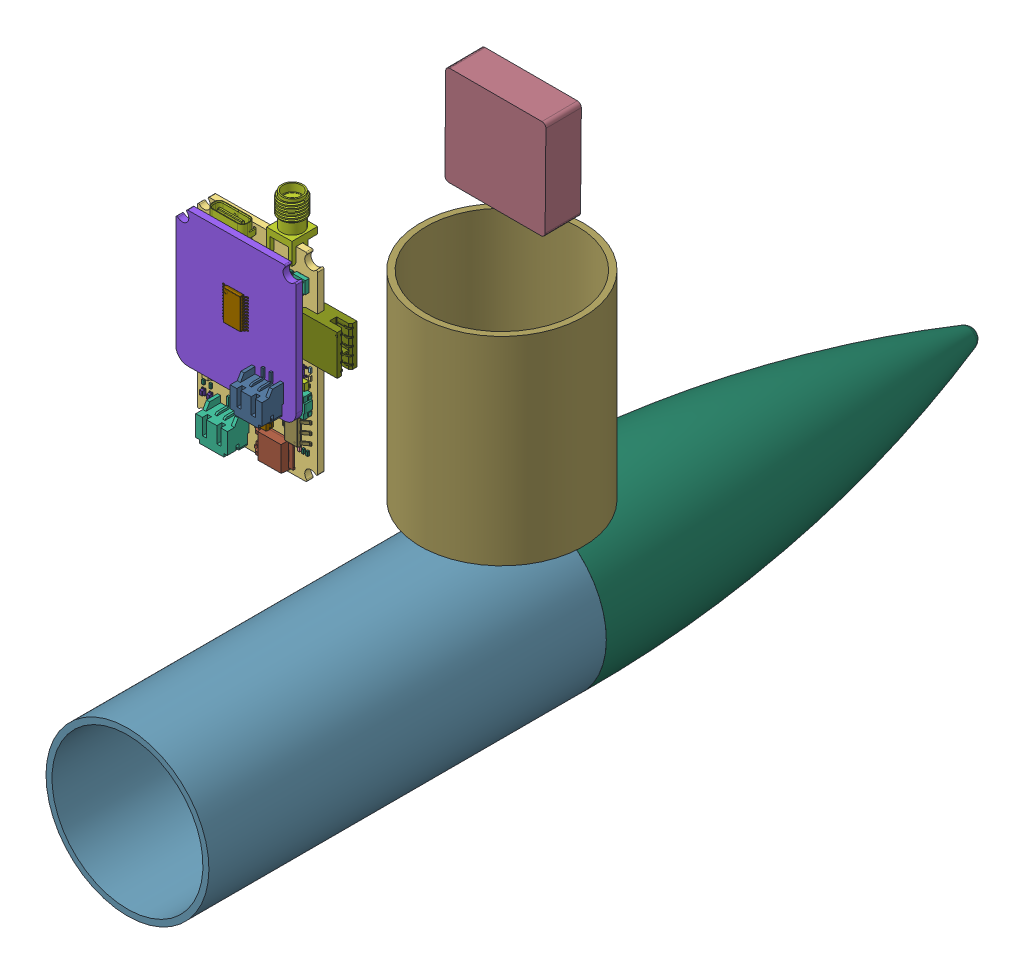
SolidWorks assembly 0. Nosecone & Avionics Bay Assembly, configuration Default. Lengths in mm.
Overall size (73.27 162.42 213).
85 component instances, 51 part files, 7 mates.
Components (placement in the parent):
- Barrel-jack female-1: Barrel-jack female [Default] at (-3.0127 -6.7721 47.1795) size (11 11 23.95)
- 18650 Long-1: 18650 Long [Default] at (0 0 34.458) x (0.762062 0.647505 0) z (-0.647505 0.762062 0) size (18.9 70 18.9)
- Firefly-mini-MBA-1: Firefly-mini-MBA [Default] at (-13.2772 55.7989 31.9723) x (0.999962 0 -0.008727) z (0.008727 0 0.999962) size (54.52 77.58 19.6)
  - Firefly-mini-1: Firefly-mini [Default] at (-8.0346 2.0358 39.383) size (54.52 77.58 14.1)
    - Firefly-mini_BOARD-1: Firefly-mini_BOARD [Default] at origin size (30 50 1.6)
    - QFP50P1200X1200X160-64N_CMP-020-00025-2-1: QFP50P1200X1200X160-64N_CMP-020-00025-2 [Default] at (24.892 39.878 1.5689) x (0 -1 0) z (0 0 1) size (11.99 11.99 1.61)
    - BMP388_CMP-004-000000-2-1: BMP388_CMP-004-000000-2 [Default] at (15.748 49.784 1.5689) size (2 2 1.1)
    - JST-_S2B-PH-SM4-TB(LF)(SN)-2_V_CMP-1755-00001-1-1: JST-_S2B-PH-SM4-TB(LF)(SN)-2_V_CMP-1755-00001-1 [Default] at (19 14.5 1.5689) size (7.9 8.6 5.6)
    - VALCON_CSP-USC16-TR_CMP-042-000000-3-1: VALCON_CSP-USC16-TR_CMP-042-000000-3 [Default] at (19.967 53.594 1.5689) x (-1 0 0) z (0 0 1) size (8.94 7.75 4.26)
    - RES-0402_CMP-009-00235-1-1: RES-0402_CMP-009-00235-1 [Default] at (17.145 52.578 1.5689) size (1.1 0.55 0.4)
    - RES-0402_CMP-009-00235-1-2: RES-0402_CMP-009-00235-1 [Default] at (22.225 52.578 1.5689) x (-1 0 0) z (0 0 1) size (1.1 0.55 0.4)
    - FP-TAJA-MFG_CMP-001-00183-1-1: FP-TAJA-MFG_CMP-001-00183-1 [Default] at (27.432 18.542 1.5689) x (-1 0 0) z (0 0 1) size (3.2 1.6 1.8)
    - KEMT-T491-B_M_CMP-001-00181-1-1: KEMT-T491-B_M_CMP-001-00181-1 [Default] at (27.813 21.336 1.5689) x (-1 0 0) z (0 0 1) size (4.14 3 2.1)
    - FP-L78M05ABDT-TR-MFG_CMP-019-00057-2-1: FP-L78M05ABDT-TR-MFG_CMP-019-00057-2 [Default] at (30.2115 14.083 1.5689) x (0 -1 0) z (0 0 1) size (6.54 9.67 2.3)
    - FP-AMS1117-IPC_B_CMP-019-00058-1-1: FP-AMS1117-IPC_B_CMP-019-00058-1 [Default] at (35.052 21.209 1.5689) x (-1 0 0) z (0 0 1) size (7.05 6.59 2.14)
    - LoRa-CC68-868-TCXO-Footprint-1_CMP-00025-00003-3-2: LoRa-CC68-868-TCXO-Footprint-1_CMP-00025-00003-3 [Default] at (21.717 43.815 0.0305) x (1 0 0) z (0 0 -1) size (16 16 2.1)
    - QUEC-L80-M39-12_V_CMP-021-00008-3-1: QUEC-L80-M39-12_V_CMP-021-00008-3 [Default] at (25 22.5 0.0305) x (-1 0 0) z (0 0 -1) size (16 16 6.95)
    - CAP-0402_CMP-001-00142-1-1: CAP-0402_CMP-001-00142-1 [Default] at (17.399 49.911 1.5689) x (0 1 0) z (0 0 1) size (1.05 0.55 0.55)
    - CAP-0402_CMP-001-00142-1-2: CAP-0402_CMP-001-00142-1 [Default] at (15.24 51.562 1.5689) size (1.05 0.55 0.55)
    - 009159010061911-Footprint-1_CMP-002-00088-4-1: 009159010061911-Footprint-1_CMP-002-00088-4 [Default] at (37.715 43 1.5689) x (0 -1 0) z (0 0 1) size (10 10 5)
    - FP-SOT23-IPC_C_CMP-013-00038-1-1: FP-SOT23-IPC_C_CMP-013-00038-1 [Default] at (36.068 34.036 1.5689) x (-1 0 0) z (0 0 1) size (2.82 2.9 1.25)
    - FP-YZT0012A-IPC_C_CMP-016-00011-1-1: FP-YZT0012A-IPC_C_CMP-016-00011-1 [Default] at (34.3123 48.6187 1.5689) x (0.707107 0.707107 0) z (0 0 1) size (1.38 1.88 0.64)
    - RES-0402_CMP-009-00211-1-1: RES-0402_CMP-009-00211-1 [Default] at (15.367 48.133 1.5689) size (1.1 0.55 0.4)
    - RES-0402_CMP-009-00211-1-2: RES-0402_CMP-009-00211-1 [Default] at (17.018 51.562 1.5689) size (1.1 0.55 0.4)
    - SOT95P280X145-5N_CMP-122-000000-3-1: SOT95P280X145-5N_CMP-122-000000-3 [Default] at (30.495 26.101 1.5689) x (-1 0 0) z (0 0 1) size (2.8 2.9 1.2)
    - RES-0402_CMP-009-00191-1-1: RES-0402_CMP-009-00191-1 [Default] at (32.766 52.451 1.5689) x (0 1 0) z (0 0 1) size (1.1 0.55 0.4)
    - RES-0402_CMP-009-00191-1-2: RES-0402_CMP-009-00191-1 [Default] at (38.354 33.274 1.5689) x (0 1 0) z (0 0 1) size (1.1 0.55 0.4)
    - RES-0402_CMP-009-00191-1-3: RES-0402_CMP-009-00191-1 [Default] at (11.43 30.607 1.5689) x (0 -1 0) z (0 0 1) size (1.1 0.55 0.4)
    - RES-0402_CMP-009-00191-1-4: RES-0402_CMP-009-00191-1 [Default] at (17.145 39.497 1.5689) x (0.707107 -0.707107 0) z (0 0 1) size (1.1 0.55 0.4)
    - RES-0402_CMP-009-00191-1-5: RES-0402_CMP-009-00191-1 [Default] at (12.573 23.622 1.5689) x (-1 0 0) z (0 0 1) size (1.1 0.55 0.4)
    - RES-0402_CMP-009-00191-1-6: RES-0402_CMP-009-00191-1 [Default] at (14.732 43.942 1.5689) x (0 1 0) z (0 0 1) size (1.1 0.55 0.4)
    - RES-0402_CMP-009-00191-1-7: RES-0402_CMP-009-00191-1 [Default] at (23.241 19.05 1.5689) x (-1 0 0) z (0 0 1) size (1.1 0.55 0.4)
    - CAP-0402_CMP-001-00135-1-1: CAP-0402_CMP-001-00135-1 [Default] at (29.083 23.876 1.5689) size (1.05 0.55 0.55)
    - CAP-0402_CMP-001-00135-1-2: CAP-0402_CMP-001-00135-1 [Default] at (31.369 23.876 1.5689) x (-1 0 0) z (0 0 1) size (1.05 0.55 0.55)
    - CAP-0402_CMP-001-00135-1-3: CAP-0402_CMP-001-00135-1 [Default] at (20.828 48.895 1.5689) x (-1 0 0) z (0 0 1) size (1.05 0.55 0.55)
    - CAP-0402_CMP-001-00142-1-3: CAP-0402_CMP-001-00142-1 [Default] at (36.068 50.673 1.5689) x (-1 0 0) z (0 0 1) size (1.05 0.55 0.55)
    - CAP-0402_CMP-001-00142-1-4: CAP-0402_CMP-001-00142-1 [Default] at (33.655 52.451 1.5689) x (0 1 0) z (0 0 1) size (1.05 0.55 0.55)
    - CAP-0402_CMP-001-00142-1-5: CAP-0402_CMP-001-00142-1 [Default] at (33.528 54.102 1.5689) size (1.05 0.55 0.55)
    - CAP-0402_CMP-001-00142-1-6: CAP-0402_CMP-001-00142-1 [Default] at (11.938 41.148 1.5689) x (-1 0 0) z (0 0 1) size (1.05 0.55 0.55)
    - CAP-0402_CMP-001-00142-1-7: CAP-0402_CMP-001-00142-1 [Default] at (14.732 46.101 1.5689) x (0 1 0) z (0 0 1) size (1.05 0.55 0.55)
    - CAP-0402_CMP-001-00142-1-8: CAP-0402_CMP-001-00142-1 [Default] at (32.131 43.307 1.5689) x (0 1 0) z (0 0 1) size (1.05 0.55 0.55)
    - CAP-0402_CMP-001-00142-1-9: CAP-0402_CMP-001-00142-1 [Default] at (17.526 42.672 1.5689) x (0 -1 0) z (0 0 1) size (1.05 0.55 0.55)
    - CAP-0402_CMP-001-00142-1-10: CAP-0402_CMP-001-00142-1 [Default] at (29.845 45.466 1.5689) x (-1 0 0) z (0 0 1) size (1.05 0.55 0.55)
    - CAP-0402_CMP-001-00142-1-11: CAP-0402_CMP-001-00142-1 [Default] at (33.147 43.307 1.5689) x (0 1 0) z (0 0 1) size (1.05 0.55 0.55)
    - CAP-0402_CMP-001-00142-1-12: CAP-0402_CMP-001-00142-1 [Default] at (29.845 34.163 1.5689) x (-1 0 0) z (0 0 1) size (1.05 0.55 0.55)
    - CAP-0402_CMP-001-00142-1-13: CAP-0402_CMP-001-00142-1 [Default] at (20.828 47.879 1.5689) x (-1 0 0) z (0 0 1) size (1.05 0.55 0.55)
    - CAP-0402_CMP-001-00142-1-14: CAP-0402_CMP-001-00142-1 [Default] at (37.719 16.637 1.5689) x (0 1 0) z (0 0 1) size (1.05 0.55 0.55)
    - CAP-0402_CMP-001-00142-1-15: CAP-0402_CMP-001-00142-1 [Default] at (36.703 16.637 1.5689) x (0 1 0) z (0 0 1) size (1.05 0.55 0.55)
    - RES-0402_CMP-009-00218-1-1: RES-0402_CMP-009-00218-1 [Default] at (38.354 35.052 1.5689) x (0 -1 0) z (0 0 1) size (1.1 0.55 0.4)
    - MLT-5020_CMP-00027-00002-1-1: MLT-5020_CMP-00027-00002-1 [Default] at (36.195 27.559 1.5689) x (-1 0 0) z (0 0 1) size (5 5 2)
    - MCC-SOD-123FL_V_CMP-004-00034-1-1: MCC-SOD-123FL_V_CMP-004-00034-1 [Default] at (36.322 31.369 1.5689) size (3.7 1.9 1.2)
    - SOIC127P790X216-8N_CMP-040-000000-2-1: SOIC127P790X216-8N_CMP-040-000000-2 [Default] at (13.335 36.068 1.5689) x (0 1 0) z (0 0 1) size (7.9 5.28 2.16)
    - FP-EVQ-P7A01P-MFG_CMP-011-00021-3-1: FP-EVQ-P7A01P-MFG_CMP-011-00021-3 [Default] at (12 45 1.5689) x (0 -1 0) z (0 0 1) size (4.7 3.55 1.35)
    - FP-EVQ-P7A01P-MFG_CMP-011-00021-3-2: FP-EVQ-P7A01P-MFG_CMP-011-00021-3 [Default] at (12 27 1.5689) x (0 -1 0) z (0 0 1) size (4.7 3.55 1.35)
    - FP-BLM15-0_05-IPC_A_CMP-006-00022-1-1: FP-BLM15-0_05-IPC_A_CMP-006-00022-1 [Default] at (20.828 49.784 1.5689) size (1.1 0.6 0.65)
    - CAP-0402_CMP-001-00139-1-1: CAP-0402_CMP-001-00139-1 [Default] at (17.272 36.83 1.5689) x (0.707107 -0.707107 0) z (0 0 1) size (1.05 0.55 0.55)
    - CAP-0402_CMP-001-00139-1-2: CAP-0402_CMP-001-00139-1 [Default] at (17.272 38.227 1.5689) x (0.707107 -0.707107 0) z (0 0 1) size (1.05 0.55 0.55)
    - FP-NX3215SA-MFG_CMP-003-00031-1-1: FP-NX3215SA-MFG_CMP-003-00031-1 [Default] at (29.464 48.641 1.5689) x (0 1 0) z (0 0 1) size (3.21 1.51 0.9)
    - FP-NX3225GA-MFG_CMP-003-00030-1-1: FP-NX3225GA-MFG_CMP-003-00030-1 [Default] at (25.4 49.022 1.5689) x (-1 0 0) z (0 0 1) size (3.21 2.51 0.9)
    - THRMC1608X95N_CMP-038-000000-2-1: THRMC1608X95N_CMP-038-000000-2 [Default] at (19.939 21.209 1.5689) x (0 1 0) z (0 0 1) size (1.6 0.8 0.45)
    - RES-0402_CMP-009-00210-1-1: RES-0402_CMP-009-00210-1 [Default] at (11.684 19.304 1.5689) x (0 1 0) z (0 0 1) size (1.1 0.55 0.4)
    - RES-0402_CMP-009-00210-1-2: RES-0402_CMP-009-00210-1 [Default] at (13.462 19.304 1.5689) x (0 1 0) z (0 0 1) size (1.1 0.55 0.4)
    - AO-SOT-23-3L_V_CMP-013-00037-1-1: AO-SOT-23-3L_V_CMP-013-00037-1 [Default] at (22.479 21.209 1.5689) x (0 1 0) z (0 0 1) size (3 3.1 1.25)
    - FP-LTST-C190GKT-MFG_CMP-00026-00001-1-1: FP-LTST-C190GKT-MFG_CMP-00026-00001-1 [Default] at (13.462 17.145 1.5689) x (0 1 0) z (0 0 1) size (1.6 0.8 0.9)
    - FP-LTST-C190GKT-MFG_CMP-00026-00001-1-2: FP-LTST-C190GKT-MFG_CMP-00026-00001-1 [Default] at (11.684 17.145 1.5689) x (0 1 0) z (0 0 1) size (1.6 0.8 0.9)
    - FP-477-02-IPC_C_CMP-004-00036-1-1: FP-477-02-IPC_C_CMP-004-00036-1 [Default] at (26.035 54.102 1.5689) x (0 1 0) z (0 0 1) size (2.5 1.35 1.13)
    - CAP-0402_CMP-001-02164-2-1: CAP-0402_CMP-001-02164-2 [Default] at (23.114 48.768 1.5689) x (0 -1 0) z (0 0 1) size (1.05 0.55 0.55)
    - CAP-0402_CMP-001-02164-2-2: CAP-0402_CMP-001-02164-2 [Default] at (25.527 50.927 1.5689) size (1.05 0.55 0.55)
    - CAP-0402_CMP-001-02165-2-1: CAP-0402_CMP-001-02165-2 [Default] at (30.861 49.53 1.5689) x (0 1 0) z (0 0 1) size (1.05 0.55 0.55)
    - CAP-0402_CMP-001-02165-2-2: CAP-0402_CMP-001-02165-2 [Default] at (30.861 47.879 1.5689) x (0 -1 0) z (0 0 1) size (1.05 0.55 0.55)
    - LED_WS2812-2020_CMP-002-000000-1-1: LED_WS2812-2020_CMP-002-000000-1 [Default] at (12.7 21.59 1.5689) x (-1 0 0) z (0 0 1) size (2.2 2 0.84)
    - CAP-0402_CMP-001-00136-1-1: CAP-0402_CMP-001-00136-1 [Default] at (35.687 16.637 1.5689) x (0 1 0) z (0 0 1) size (1.05 0.55 0.55)
    - FP-DF40HC_4_0_-40DS-0_4V-MFG_CMP-002-00094-1-1: FP-DF40HC_4_0_-40DS-0_4V-MFG_CMP-002-00094-1 [Default] at (25 30 1.5689) size (10.6 3.38 4.09)
    - TDK-QFN-24_L_CMP-010-00033-1-1: TDK-QFN-24_L_CMP-010-00033-1 [Default] at (36.338 53.162 1.5689) x (0 -1 0) z (0 0 1) size (3.1 3.1 1.05)
    - FP-SMA-J-P-H-ST-EM1-MFG_CMP-002-00096-1-1: FP-SMA-J-P-H-ST-EM1-MFG_CMP-002-00096-1 [Default] at (31.496 64.318 0.0305) x (1 0 0) z (0 0 -1) size (8.31 13.33 8.32)
  - Firefly-mini-expansion-1: Firefly-mini-expansion [Default] at (-8.0346 2.0358 44.8565) size (30 34 8.46)
    - Firefly-mini-expansion_BOARD-1: Firefly-mini-expansion_BOARD [Default] at origin size (30 34 1.62)
    - TI-PW24_M_CMP-015-00009-1-1: TI-PW24_M_CMP-015-00009-1 [Default] at (25 44.831 1.594) size (6.4 7.8 1.13)
    - JST-_S2B-PH-SM4-TB(LF)(SN)-2_V_CMP-002-00031-2-1: JST-_S2B-PH-SM4-TB(LF)(SN)-2_V_CMP-002-00031-2 [Default] at (33 30.5 1.594) size (7.9 8.6 5.6)
    - FP-DF40C-40DP-0_4V_51-MFG_CMP-002-00095-1-1: FP-DF40C-40DP-0_4V_51-MFG_CMP-002-00095-1 [Default] at (25 30 0.0254) x (1 0 0) z (0 0 -1) size (9.53 2.97 1.29)
- 38mm-1: 38mm [Default] at (23.7437 46.9415 31.0299) size (41 50 41)
- RS GPS Dongle-1: RS GPS Dongle [Default] at (21.6502 121.4366 21.6442) x (-0.008727 -0.999962 0) z (-0.999924 0.008726 0.008727) size (25 9 25)
- Avionics Bay Tube-1: Avionics Bay Tube [Default] at (0 0 101.5) x (-0.837169 0.546944 0) z (-0.546944 -0.837169 0) size (41 100 41)
- 3D Printed Nose Cone-1: 3D Printed Nose Cone [Default] at origin size (41 41 183.96)
- 18650 Long-2: 18650 Long [Default] at (0 0 -35.542) x (1 0 0) z (0 1 0) size (18.9 70 18.9)
Mates (geometry in assembly coordinates):
- Concentric3: concentric aligned: cylinder of Avionics Bay Tube-1 through (0 0 1.5) axis (0 0 1) radius 19; cylinder of 3D Printed Nose Cone-1 through (0 0 0) axis (0 0 1) radius 19
- Coincident16: coincident anti-aligned: plane of Avionics Bay Tube-1 through (0 0 1.5) normal (0 0 -1); plane of 3D Printed Nose Cone-1 through (19 0 1.5) normal (0 0 1)
- Coincident17: coordinate: point of 3D Printed Nose Cone-1
- Coincident18: coincident anti-aligned: plane of 3D Printed Nose Cone-1 through (0 0 -70.542) normal (0 0 1); plane of 18650 Long-2 through (0 0 -70.542) normal (0 0 -1)
- Concentric4: concentric anti-aligned: cylinder of 3D Printed Nose Cone-1 through (0 0 0) axis (0 0 1) radius 9.5; cylinder of 18650 Long-2 through (0 0 -0.542) axis (0 0 -1) radius 9.45
- Coincident19: coincident anti-aligned: plane of 18650 Long-1 through (0 0 -0.542) normal (0 0 -1); plane of 18650 Long-2 through (0 0 -0.542) normal (0 0 1)
- Concentric5: concentric anti-aligned: cylinder of 18650 Long-1 through (0 0 69.458) axis (0 0 -1) radius 9.45; cylinder of 3D Printed Nose Cone-1 through (0 0 0) axis (0 0 1) radius 9.5
